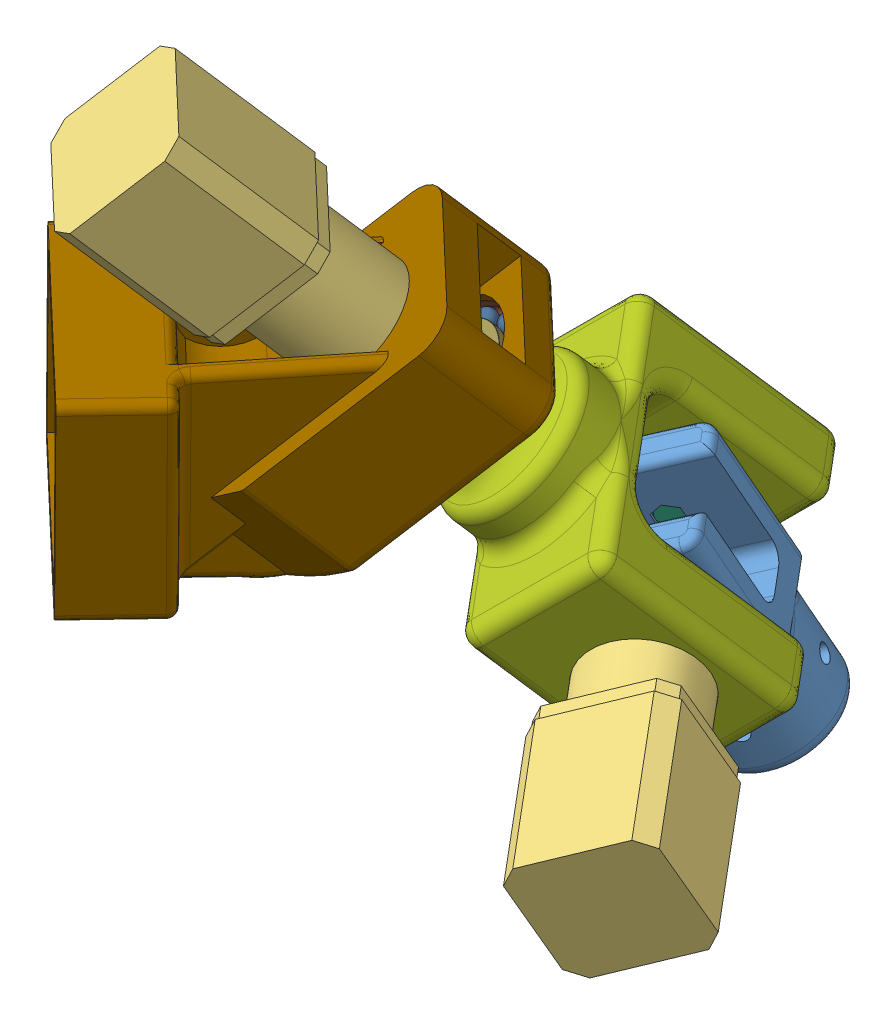
SolidWorks assembly AssiemeSpallaAvamb, configuration Default. Lengths in mm.
Overall size (218.8 222.82 203.47).
30 component instances, 12 part files, 18 mates.
Components (placement in the parent):
- Avamb-1: Avamb [Default] at (-57.9128 -289.3225 521.5345) x (0.602435 -0.238977 0.761552) z (0.181017 -0.888357 -0.421965) size (43 56.64 85)
- flangia_spalla-1: flangia_spalla [Default] at (-55.6895 -273.8734 537.3609) x (0.181017 -0.888357 -0.421965) z (0.602435 -0.238977 0.761552) size (32 32 13)
- motore_spalla-1: motore_spalla [Default] at (39.8175 -313.7526 645.2103) x (0.193212 -0.882085 -0.429644) z (-0.602435 0.238977 -0.761552) size (42.3 42.3 104)
  - 17HS19-1684S-PG14-1: 17HS19-1684S-PG14 [Default] at (-7.2931 5.4422 42.5) size (42.3 42.3 85)
  - albero_motore-1: albero_motore [Default] at (-7.2931 5.4422 127.5) x (0 0 1) z (-0.437031 -0.899446 0) size (19 8 8)
- boccola_spalla-1: boccola_spalla [Default] at (-73.883 -266.6563 514.362) x (-0.283955 -0.955874 -0.07533) z (-0.602435 0.238977 -0.761552) size (10 10 14)
- hex bolt gradeab_iso-7: hex bolt gradeab_iso [ISO 4014 - M5 x 25 x 16-N] at (-67.678 -269.1178 522.206) x (-0.602435 0.238977 -0.761552) z (-0.23192 -0.96537 -0.119473) size (28.5 9.24 8)
- SpallaSpalla-1: SpallaSpalla [Default] at (-95.8325 -215.2579 575.2983) x (-0.602435 0.238977 -0.761552) z (0.431754 -0.704914 -0.562748) size (90 59.46 110)
- Bearig 8x22x7-4: Bearig 8x22x7 [Default] at (-77.1964 -265.3419 510.1735) x (-0.408264 0.727602 0.551286) z (0.602435 -0.238977 0.761552) size (22 22 7)
- assieme_Spalla_new-1: assieme_Spalla_new [Default] at (-139.3977 -227.8852 619.5028) x (-0.722976 0.102605 -0.683211) z (-0.076079 -0.99472 -0.068881) size (74.81 160.63 140.24)
  - motore_spalla-1: motore_spalla [Default] at (7.2961 -48.9495 -116.1114) x (1 0.000382 -0.000382) z (0 0.707107 0.707107) size (42.3 42.3 104) (flexible)
    - 17HS19-1684S-PG14-1: 17HS19-1684S-PG14 [Default] at (-7.2931 5.4422 42.5) size (42.3 42.3 85)
    - albero_motore-1: albero_motore [Default] at (-7.2931 5.4422 127.5) x (0 0 1) z (-0.943838 0.330409 0) size (19 8 8)
  - supporto_spalla_CHIUSO-1: supporto_spalla_CHIUSO [Default] x (1 0 0) z (0 -1 0) size (70 90.09 160.61)
  - flangia_spalla-1: flangia_spalla [Default] at (0 62.0226 -12.8302) x (0.537947 -0.596076 0.596076) z (0 -0.707107 -0.707107) size (32 32 13)
  - SKF_16006-1: SKF_16006 [Default] at (0 71.215 -3.6378) x (0 -0.707107 -0.707107) z (0.873766 -0.343899 0.343899) size (9 55 55)
    - SKF_16006_16-1: SKF_16006_16 [Default] x (1 0 0) z (0 -0.5 0.866025) size (6.35 6.35 6.35)
    - SKF_16006_16-2: SKF_16006_16 [Default] x (1 0 0) z (0 -0.866025 0.5) size (6.35 6.35 6.35)
    - SKF_16006_16-3: SKF_16006_16 [Default] x (1 0 0) z (0 -1 0) size (6.35 6.35 6.35)
    - SKF_16006_16-4: SKF_16006_16 [Default] x (1 0 0) z (0 -0.866025 -0.5) size (6.35 6.35 6.35)
    - SKF_16006_16-5: SKF_16006_16 [Default] x (1 0 0) z (0 -0.5 -0.866025) size (6.35 6.35 6.35)
    - SKF_16006_16-6: SKF_16006_16 [Default] x (1 0 0) z (0 0 -1) size (6.35 6.35 6.35)
    - SKF_16006_16-7: SKF_16006_16 [Default] x (1 0 0) z (0 0.5 -0.866025) size (6.35 6.35 6.35)
    - SKF_16006_16-8: SKF_16006_16 [Default] x (1 0 0) z (0 0.866025 -0.5) size (6.35 6.35 6.35)
    - SKF_16006_16-9: SKF_16006_16 [Default] x (1 0 0) z (0 1 0) size (6.35 6.35 6.35)
    - SKF_16006_16-10: SKF_16006_16 [Default] x (1 0 0) z (0 0.866025 0.5) size (6.35 6.35 6.35)
    - SKF_16006_16-11: SKF_16006_16 [Default] x (1 0 0) z (0 0.5 0.866025) size (6.35 6.35 6.35)
    - SKF_16006_16-12: SKF_16006_16 [Default] at origin size (6.35 6.35 6.35)
    - SKF_16006_29-1: SKF_16006_29 [Default] at origin size (9 55 55)
    - SKF_16006_31-1: SKF_16006_31 [Default] at origin size (9 37.7 37.7)
Mates (geometry in assembly coordinates):
- Concentrico16: concentric anti-aligned: cylinder of Avamb-1 through (-49.1832 -276.4544 545.5857) axis (-0.602435 0.238977 -0.761552) radius 8; cylinder of flangia_spalla-1 through (-55.6895 -273.8734 537.3609) axis (0.602435 -0.238977 0.761552) radius 4
- Coincidente17: coincident anti-aligned: plane of Avamb-1 through (-53.8822 -274.5904 539.6455) normal (-0.602435 0.238977 -0.761552); plane of flangia_spalla-1 through (-53.8822 -274.5904 539.6455) normal (0.602435 -0.238977 0.761552)
- Concentrico18: concentric aligned: cylinder of Avamb-1 through (-53.0354 -284.7249 532.9065) axis (0.602435 -0.238977 0.761552) radius 2.1; cylinder of flangia_spalla-1 through (-53.5173 -284.5337 532.2973) axis (0.602435 -0.238977 0.761552) radius 2
- Parallelo9: parallel anti-aligned: plane of Avamb-1 through (-61.5673 -240.8519 512.717) normal (-0.602435 0.238977 -0.761552); plane of SpallaSpalla-1 through (-66.8197 -235.4323 516.209) normal (0.602435 -0.238977 0.761552)
- Concentrico19: concentric anti-aligned: circle of Avamb-1; circle of SpallaSpalla-1
- Concentrico20: concentric anti-aligned: circle of SpallaSpalla-1; circle of Bearig 8x22x7-4
- Coincidente18: coincident anti-aligned: plane of SpallaSpalla-1 through (-79.305 -264.5055 507.508) normal (0.602435 -0.238977 0.761552); plane of Bearig 8x22x7-4 through (-79.305 -264.5055 507.508) normal (-0.602435 0.238977 -0.761552)
- Coincidente19: coincident anti-aligned: plane of Avamb-1 through (-75.0879 -266.1784 512.8389) normal (-0.602435 0.238977 -0.761552); plane of Bearig 8x22x7-4 through (-75.0879 -266.1784 512.8389) normal (0.602435 -0.238977 0.761552)
- Concentrico21: concentric anti-aligned: cylinder of hex bolt gradeab_iso-7 through (-67.678 -269.1178 522.206) axis (0.602435 -0.238977 0.761552) radius 2.5; cylinder of SpallaSpalla-1 through (-82.3774 -263.2867 503.6241) axis (-0.602435 0.238977 -0.761552) radius 8
- Parallelo10: parallel aligned: plane of Avamb-1 through (-73.4022 -267.786 522.5563) normal (0.777371 0.39206 -0.491918); plane of hex bolt gradeab_iso-7 through (-67.095 -264.6616 518.5474) normal (0.777371 0.39206 -0.491918)
- Coincidente20: coincident anti-aligned: plane of Avamb-1 through (-66.1662 -286.0485 511.1013) normal (0.602435 -0.238977 0.761552); plane of hex bolt gradeab_iso-7 through (-66.259 -268.7647 516.5984) normal (-0.602435 0.238977 -0.761552)
- Concentrico22: concentric aligned: cylinder of boccola_spalla-1 through (-79.305 -264.5055 507.508) axis (0.602435 -0.238977 0.761552) radius 3.9; cylinder of hex bolt gradeab_iso-7 through (-67.678 -269.1178 522.206) axis (0.602435 -0.238977 0.761552) radius 2.5
- Coincidente22: coincident anti-aligned: plane of Avamb-1 through (-61.5673 -240.8519 512.717) normal (-0.602435 0.238977 -0.761552); plane of boccola_spalla-1 through (-73.883 -266.6563 514.362) normal (0.602435 -0.238977 0.761552)
- Parallelo11: parallel aligned: plane of motore_spalla-1/17HS19-1684S-PG14-1 through (8.5903 -299.3723 618.6185) normal (0.602435 -0.238977 0.761552); plane of SpallaSpalla-1 through (-42.3303 -313.1988 561.3305) normal (0.602435 -0.238977 0.761552)
- Coincidente23: coincident anti-aligned: plane of motore_spalla-1/17HS19-1684S-PG14-1 through (-41.4118 -279.5372 555.4097) normal (-0.602435 0.238977 -0.761552); plane of SpallaSpalla-1 through (-41.4118 -279.5372 555.4097) normal (0.602435 -0.238977 0.761552)
- Concentrico23: concentric aligned: cylinder of motore_spalla-1/17HS19-1684S-PG14-1 through (-41.4118 -279.5372 555.4097) axis (0.602435 -0.238977 0.761552) radius 18; cylinder of SpallaSpalla-1 through (-41.4118 -279.5372 555.4097) axis (0.602435 -0.238977 0.761552) radius 18.1
- Concentrico24: concentric aligned: cylinder of SpallaSpalla-1 through (-85.0386 -232.8807 561.2296) axis (-0.431754 0.704914 0.562748) radius 14.9; cylinder of assieme_Spalla_new-1/SKF_16006-1/SKF_16006_31-1 through (-133.3951 -153.9304 624.2574) axis (-0.431754 0.704914 0.562748) radius 15
- Coincidente24: coincident anti-aligned: plane of SpallaSpalla-1 through (-95.8325 -215.2579 575.2983) normal (-0.431754 0.704914 0.562748); plane of assieme_Spalla_new-1/flangia_spalla-1 through (-95.8325 -215.2579 575.2983) normal (0.431754 -0.704914 -0.562748)
